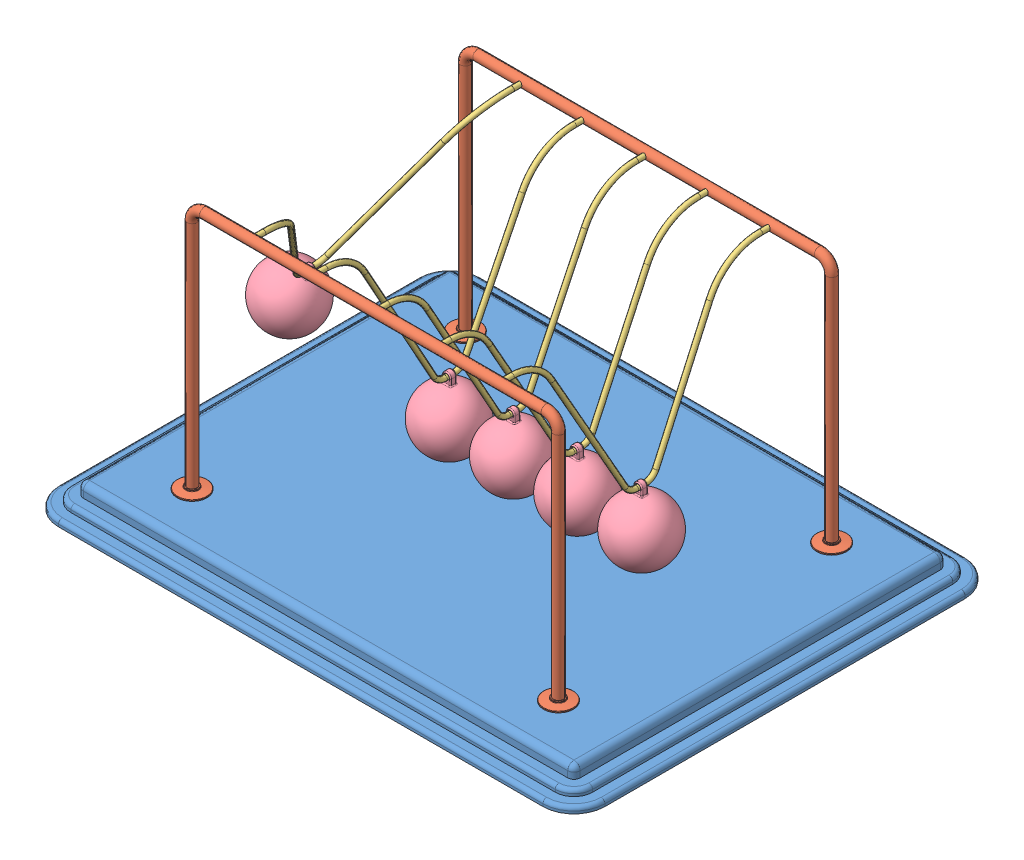
SolidWorks assembly Newtons Cradle NewtonsCradle 0251, configuration Default. Lengths in mm.
Overall size (440 222 340).
13 component instances, 4 part files, 34 mates.
Components (placement in the parent):
- Base 203.403565640195-1: Base 203.403565640195 [Default] at (-16.2968 -4.1587 11.425) size (440 20 340)
- frame NewtonsCradle 0251-1: frame NewtonsCradle 0251 [Default] at (-16.2968 144.4547 -98.575) size (319 202 24)
- frame NewtonsCradle 0251-2: frame NewtonsCradle 0251 [Default] at (-16.2968 144.4547 121.425) x (-1 0 0) z (0 0 -1) size (319 202 24)
- Hanging thing NewtonsCradle 0251-1: Hanging thing NewtonsCradle 0251 [Default] at (-157.6326 134.1825 11.425) x (0 0 1) z (-0.859985 0.510319 0) size (220 129 4)
- Hanging thing NewtonsCradle 0251-2: Hanging thing NewtonsCradle 0251 [Default] at (-66.576 122.8418 11.425) x (0 0 1) z (-0.999994 0.003446 0) size (220 129 4)
- Hanging thing NewtonsCradle 0251-3: Hanging thing NewtonsCradle 0251 [Default] at (-15.6923 122.8436 11.425) x (0 0 1) z (-0.999972 -0.007464 0) size (220 129 4)
- Hanging thing NewtonsCradle 0251-4: Hanging thing NewtonsCradle 0251 [Default] at (35.2213 122.8555 11.425) x (0 0 1) z (-0.999824 -0.018742 0) size (220 129 4)
- Hanging thing NewtonsCradle 0251-5: Hanging thing NewtonsCradle 0251 [Default] at (86.0287 122.8747 11.425) x (0 0 1) z (-0.999588 -0.028711 0) size (220 129 4)
- Sphere NewtonsCradle 0251-1: Sphere NewtonsCradle 0251 [Default] at (-195.3962 70.5436 11.425) x (0.859985 -0.510319 0) z (0 0 1) size (50 58.5 50)
- Sphere NewtonsCradle 0251-2: Sphere NewtonsCradle 0251 [Default] at (88.1533 48.9052 11.425) x (0.999588 0.028711 0) z (0 0 1) size (50 58.5 50)
- Sphere NewtonsCradle 0251-3: Sphere NewtonsCradle 0251 [Default] at (-15.14 48.8456 11.425) x (0.999972 0.007464 0) z (0 0 1) size (50 58.5 50)
- Sphere NewtonsCradle 0251-4: Sphere NewtonsCradle 0251 [Default] at (36.6081 48.8685 11.425) x (0.999824 0.018742 0) z (0 0 1) size (50 58.5 50)
- Sphere NewtonsCradle 0251-5: Sphere NewtonsCradle 0251 [Default] at (-66.831 48.8422 11.425) x (0.999994 -0.003446 0) z (0 0 1) size (50 58.5 50)
Mates (geometry in assembly coordinates):
- Coincident1: coincident anti-aligned: plane of Base-1 through (-211.2968 5.8413 156.425) normal (0 1 0); plane of frame-2 through (-175.7968 5.8413 121.425) normal (0 -1 0)
- Coincident2: coincident anti-aligned: plane of Base-1 through (-211.2968 5.8413 156.425) normal (0 1 0); plane of frame-1 through (143.2032 5.8413 -98.575) normal (0 -1 0)
- Concentric1: concentric anti-aligned: cylinder of frame-1 through (-116.2968 203.8413 -94.575) axis (0 0 -1) radius 2; cylinder of frame-2 through (-116.2968 203.8413 117.425) axis (0 0 1) radius 2
- Concentric2: concentric anti-aligned: cylinder of frame-1 through (83.7032 203.8413 -94.575) axis (0 0 -1) radius 2; cylinder of frame-2 through (83.7032 203.8413 117.425) axis (0 0 1) radius 2
- Distance1: distance = 60 mm: plane of frame-1 through (-16.2968 144.4547 -98.575) normal (0 0 1); line of Base-1 through (-211.2968 -12.1587 -158.575) axis (1 0 0)
- Distance2: distance = 60 mm: line of Base-1 through (178.7032 -12.1587 181.425) axis (-1 0 0); plane of frame-2 through (-16.2968 144.4547 121.425) normal (0 0 -1)
- Distance3: distance = 220 mm: plane of frame-2 through (-16.2968 144.4547 121.425) normal (-1 0 0); line of Base-1 through (-236.2968 -12.1587 156.425) axis (0 0 -1)
- Concentric3: concentric anti-aligned: cylinder of frame-1 through (-116.2968 203.8413 -94.575) axis (0 0 -1) radius 2; cylinder of Hanging thing-1 through (-116.2968 203.8413 111.425) axis (0 0 1) radius 2
- Concentric4: concentric anti-aligned: cylinder of frame-1 through (-116.2968 203.8413 -94.575) axis (0 0 -1) radius 2; cylinder of Hanging thing-1 through (-116.2968 203.8413 -98.575) axis (0 0 1) radius 2
- Concentric5: concentric aligned: cylinder of frame-2 through (-66.2968 203.8413 117.425) axis (0 0 1) radius 2; cylinder of Hanging thing-2 through (-66.2968 203.8413 111.425) axis (0 0 1) radius 2
- Concentric6: concentric aligned: cylinder of frame-2 through (-16.2968 203.8413 117.425) axis (0 0 1) radius 2; cylinder of Hanging thing-3 through (-16.2968 203.8413 111.425) axis (0 0 1) radius 2
- Concentric7: concentric aligned: cylinder of frame-2 through (33.7032 203.8413 117.425) axis (0 0 1) radius 2; cylinder of Hanging thing-4 through (33.7032 203.8413 111.425) axis (0 0 1) radius 2
- Concentric8: concentric aligned: cylinder of frame-2 through (83.7032 203.8413 117.425) axis (0 0 1) radius 2; cylinder of Hanging thing-5 through (83.7032 203.8413 111.425) axis (0 0 1) radius 2
- Coincident5: coincident anti-aligned: plane of frame-2 through (83.7032 203.8413 121.425) normal (0 0 -1); plane of Hanging thing-5 through (83.7032 203.8413 121.425) normal (0 0 1)
- Coincident6: coincident anti-aligned: plane of frame-2 through (33.7032 203.8413 121.425) normal (0 0 -1); plane of Hanging thing-4 through (33.7032 203.8413 121.425) normal (0 0 1)
- Coincident7: coincident anti-aligned: plane of frame-2 through (-16.2968 203.8413 121.425) normal (0 0 -1); plane of Hanging thing-3 through (-16.2968 203.8413 121.425) normal (0 0 1)
- Coincident8: coincident anti-aligned: plane of frame-2 through (-66.2968 203.8413 121.425) normal (0 0 -1); plane of Hanging thing-2 through (-66.2968 203.8413 121.425) normal (0 0 1)
- Coincident9: coincident anti-aligned: plane of frame-2 through (-116.2968 203.8413 121.425) normal (0 0 -1); plane of Hanging thing-1 through (-116.2968 203.8413 121.425) normal (0 0 1)
- Concentric9: concentric anti-aligned: cylinder of Hanging thing-1 through (-117.0163 78.8434 7.925) axis (0 0 1) radius 2; cylinder of Sphere-1 through (-117.0163 78.8434 13.925) axis (0 0 -1) radius 2
- Concentric13: concentric anti-aligned: cylinder of Hanging thing-2 through (-66.7276 78.842 7.925) axis (0 0 1) radius 2; cylinder of Sphere-5 through (-66.7276 78.842 13.925) axis (0 0 -1) radius 2
- Concentric15: concentric anti-aligned: cylinder of Hanging thing-3 through (-15.3639 78.8448 7.925) axis (0 0 1) radius 2; cylinder of Sphere-3 through (-15.3639 78.8448 13.925) axis (0 0 -1) radius 2
- Concentric16: concentric anti-aligned: cylinder of Hanging thing-5 through (87.292 78.8928 7.925) axis (0 0 1) radius 2; cylinder of Sphere-2 through (87.292 78.8928 13.925) axis (0 0 -1) radius 2
- Concentric17: concentric anti-aligned: cylinder of Hanging thing-4 through (36.0459 78.8632 7.925) axis (0 0 1) radius 2; cylinder of Sphere-4 through (36.0459 78.8632 13.925) axis (0 0 -1) radius 2
- Parallel1: parallel anti-aligned: plane of Hanging thing-1; plane of Sphere-1
- Coincident22: coincident anti-aligned: plane of Hanging thing-1; plane of Sphere-1
- Coincident12: coincident aligned: plane of Hanging thing-2 through (-66.576 122.8418 11.425) normal (0 0 1); plane of Sphere-5 through (-66.831 48.8422 11.425) normal (0 0 1)
- Coincident10: coincident aligned: plane of Hanging thing-1 through (-116.763 122.8426 11.425) normal (0 0 1); plane of Sphere-1 through (-118.5806 48.8842 11.425) normal (0 0 1)
- Coincident13: coincident anti-aligned: plane of Hanging thing-2 through (-66.576 122.8418 11.425) normal (-0.999994 0.003446 0); plane of Sphere-5 through (-66.831 48.8422 11.425) normal (0.999994 -0.003446 0)
- Coincident14: coincident anti-aligned: plane of Hanging thing-3 through (-15.6923 122.8436 11.425) normal (-0.999972 -0.007464 0); plane of Sphere-3 through (-15.14 48.8456 11.425) normal (0.999972 0.007464 0)
- Coincident15: coincident aligned: plane of Hanging thing-3 through (-15.6923 122.8436 11.425) normal (0 0 1); plane of Sphere-3 through (-15.14 48.8456 11.425) normal (0 0 1)
- Coincident18: coincident aligned: plane of Hanging thing-4 through (35.2213 122.8555 11.425) normal (0 0 1); plane of Sphere-4 through (36.6081 48.8685 11.425) normal (0 0 1)
- Coincident19: coincident anti-aligned: plane of Hanging thing-4 through (35.2213 122.8555 11.425) normal (-0.999824 -0.018742 0); plane of Sphere-4 through (36.6081 48.8685 11.425) normal (0.999824 0.018742 0)
- Coincident20: coincident anti-aligned: plane of Hanging thing-5 through (86.0287 122.8747 11.425) normal (-0.999588 -0.028711 0); plane of Sphere-2 through (88.1533 48.9052 11.425) normal (0.999588 0.028711 0)
- Coincident21: coincident aligned: plane of Hanging thing-5 through (86.0287 122.8747 11.425) normal (0 0 1); plane of Sphere-2 through (88.1533 48.9052 11.425) normal (0 0 1)
